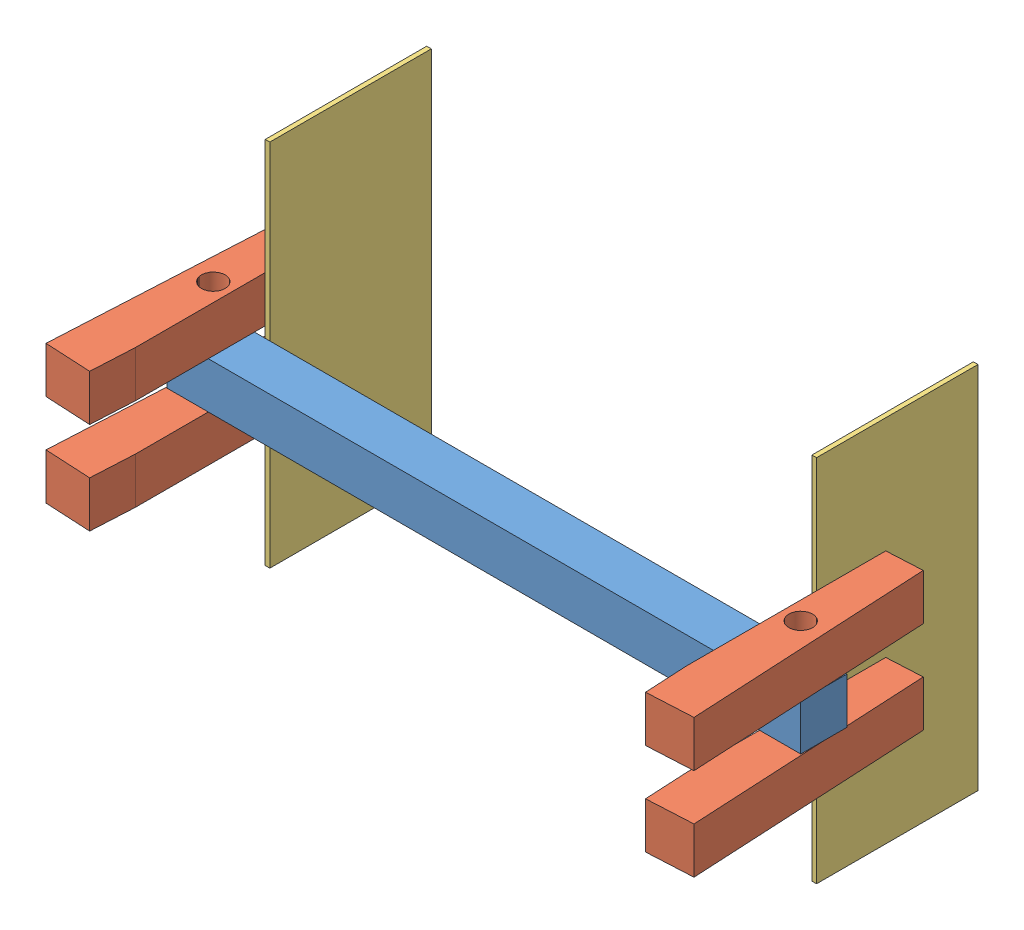
SolidWorks assembly Arm Idea 2, configuration Default. Lengths in mm.
Overall size (356.77 203.2 184.32).
8 component instances, 4 part files, 15 mates.
Components (placement in the parent):
- Back_2-1: Back_2 [Default] at (186.1527 10.0816 -4.5553) size (348.83 25.4 25.4)
- Pincher_2-1: Pincher_2 [Default] at (-153.9644 35.4816 71.5403) x (0.99863 0 0.052336) z (-0.052336 0 0.99863) size (25.4 25.4 133.4)
- Pincher_2-3: Pincher_2 [Default] at (177.4407 35.4816 71.5403) x (-0.99863 0 0.052336) z (0.052336 0 0.99863) size (25.4 25.4 133.4)
- Dice-1: Dice [Default] at (11.7382 -131.8892 -169.6553) x (1 0 0) z (0 -1 0) size (304.8 304.8 304.8) (hidden)
- Pincher_2-6: Pincher_2 [Default] at (-153.9644 -15.3184 71.5403) x (0.99863 0 0.052336) z (-0.052336 0 0.99863) size (25.4 25.4 133.4)
- Pincher_2-7: Pincher_2 [Default] at (177.4407 -15.3184 71.5403) x (-0.99863 0 0.052336) z (0.052336 0 0.99863) size (25.4 25.4 133.4)
- GrabPlatev1.2-1: GrabPlatev1.2 [Default] at (160.9632 10.0816 -67.6631) size (2.54 203.2 88.9)
- GrabPlatev1.2-2: GrabPlatev1.2 [Default] at (-140.0268 10.0816 -67.6631) size (2.54 203.2 88.9)
Mates (geometry in assembly coordinates):
- Coincident1: coincident anti-aligned: plane of Back_2-1 through (-162.6764 22.7816 8.1447) normal (0 1 0); plane of Pincher_2-1 through (-159.6653 22.7816 -62.3424) normal (0 -1 0)
- Concentric1: concentric aligned: cylinder of Back_2-1 through (-149.9764 -2.6184 -4.5553) axis (0 1 0) radius 6.35; cylinder of Pincher_2-1 through (-149.9764 22.7816 -4.5553) axis (0 1 0) radius 6.5243
- LimitAngle2: limit planar angle = 0.05236 rad aligned: plane of Pincher_2-3 through (177.4407 35.4816 71.5403) normal (0.052336 0 0.99863); plane of Back_2-1 through (-162.6764 -2.6184 8.1447) normal (0 0 1)
- LimitAngle3: limit planar angle = 0.05236 rad aligned: plane of Pincher_2-1 through (-153.9644 35.4816 71.5403) normal (-0.052336 0 0.99863); plane of Back_2-1 through (-162.6764 -2.6184 8.1447) normal (0 0 1)
- Coincident3: coincident anti-aligned: plane of Dice-1 through (-140.6618 172.9108 -17.2553) normal (0 0 1); plane of Back_2-1 through (-162.6764 -2.6184 -17.2553) normal (0 0 -1)
- LimitDistance2: limit distance = 129.2708 mm aligned: plane of Dice-1 through (11.7382 -131.8892 -169.6553) normal (0 -1 0); plane of Back_2-1 through (-162.6764 -2.6184 8.1447) normal (0 -1 0)
- Width2: width aligned: plane of Back_2-1 through (-162.6764 10.0816 -4.5553) normal (-1 0 0); plane of Back_2-1 through (186.1527 10.0816 -4.5553) normal (1 0 0); plane of Dice-1 through (164.1382 172.9108 -322.0553) normal (1 0 0); plane of Dice-1 through (-140.6618 172.9108 -322.0553) normal (-1 0 0)
- Coincident5: coincident anti-aligned: plane of Back_2-1 through (-162.6764 22.7816 8.1447) normal (0 1 0); plane of Pincher_2-3 through (183.1416 22.7816 -62.3424) normal (0 -1 0)
- Concentric2: concentric anti-aligned: cylinder of Back_2-1 through (173.4527 -2.6184 -4.5553) axis (0 1 0) radius 6.35; cylinder of Pincher_2-3 through (173.4527 48.1816 -4.5553) axis (0 -1 0) radius 6.5243
- Coincident9: coincident anti-aligned: plane of Pincher_2-7 through (163.5032 -2.6184 71.5403) normal (-1 0 0); plane of GrabPlatev1.2-1 through (163.5032 10.0816 -67.6631) normal (1 0 0)
- Distance4: distance = 50.8 mm: line of GrabPlatev1.2-1 through (163.5032 -91.5184 -112.1131) axis (0 1 0); line of Pincher_2-7 through (163.5032 -2.6184 -61.3131) axis (0 -1 0)
- Width3: width aligned: plane of Pincher_2-3 through (183.1416 48.1816 -62.3424) normal (0 1 0); plane of Pincher_2-7 through (183.1416 -28.0184 -62.3424) normal (0 -1 0); plane of GrabPlatev1.2-1 through (163.5032 111.6816 -23.2131) normal (0 1 0); plane of GrabPlatev1.2-1 through (163.5032 -91.5184 -23.2131) normal (0 -1 0)
- Coincident11: coincident anti-aligned: plane of Pincher_2-1 through (-140.0268 22.7816 71.5403) normal (1 0 0); plane of GrabPlatev1.2-2 through (-140.0268 10.0816 -67.6631) normal (-1 0 0)
- Distance5: distance = 50.8 mm: line of GrabPlatev1.2-2 through (-140.0268 -91.5184 -112.1131) axis (0 1 0); line of Pincher_2-1 through (-140.0268 22.7816 -61.3131) axis (0 1 0)
- Width4: width aligned: plane of Pincher_2-1 through (-159.6653 48.1816 -62.3424) normal (0 1 0); plane of Pincher_2-6 through (-159.6653 -28.0184 -62.3424) normal (0 -1 0); plane of GrabPlatev1.2-2 through (-137.4868 111.6816 -23.2131) normal (0 1 0); plane of GrabPlatev1.2-2 through (-137.4868 -91.5184 -23.2131) normal (0 -1 0)
